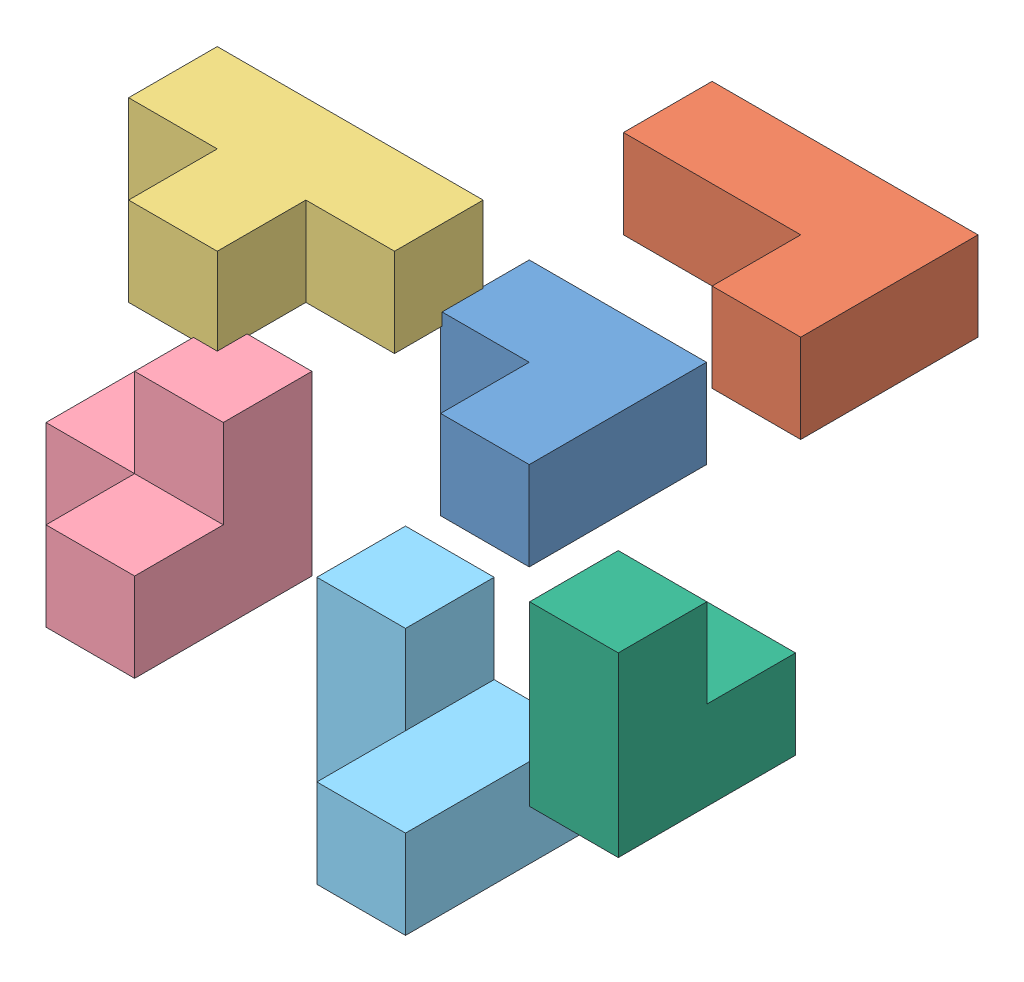
SolidWorks assembly DE_SOMA cube 00, configuration Default. Lengths in mm.
Overall size (171.15 133.48 145.48).
6 component instances, 6 part files, 0 mates.
Components (placement in the parent):
- DE_SOMA 01 L1-1: DE_SOMA 01 L1 [Default] at (10.6561 25.1028 44.3326) size (50.8 25.4 50.8)
- DE_SOMA 02 L2-1: DE_SOMA 02 L2 [Default] at (36.9544 56.8239 5.5359) size (76.2 25.4 50.8)
- DE_SOMA 03 Tee-1: DE_SOMA 03 Tee [Default] at (-52.4123 46.9874 57.9698) size (76.2 25.4 50.8)
- DE_SOMA 04 Cap-1: DE_SOMA 04 Cap [Default] at (-46.5421 -3.2058 100.214) size (50.8 50.8 50.8)
- DE_SOMA 05 sister1-1: DE_SOMA 05 sister1 [Default] at (8.0204 -51.2567 77.1588) size (50.8 50.8 50.8)
- DE_SOMA 06 sister2-1: DE_SOMA 06 sister2 [Default] at (55.2425 -15.1995 63.4095) size (50.8 50.8 50.8)
